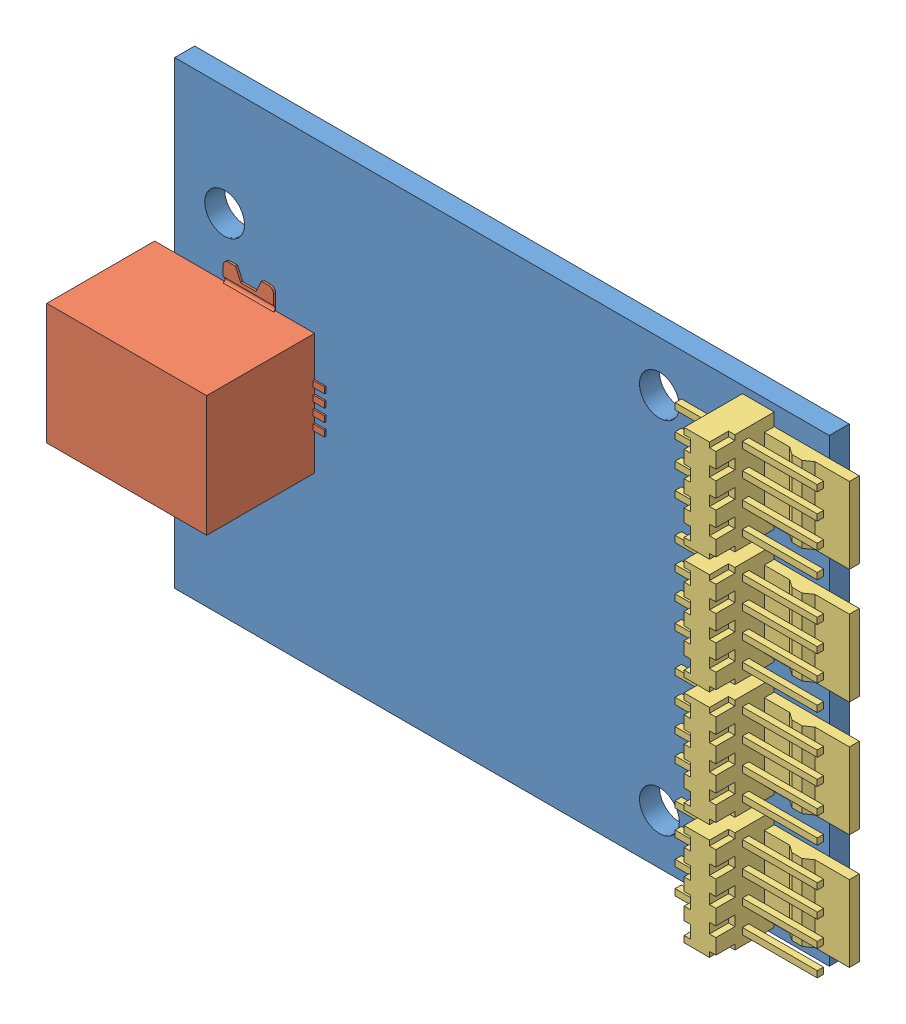
SolidWorks assembly UsbBoard, configuration Défaut. Lengths in mm.
Overall size (70.5 46 14.87).
6 component instances, 3 part files, 5 mates.
Components (placement in the parent):
- UsbBoard-1: UsbBoard [Défaut] at (-58.0315 -11.6271 69) size (65.5 46 2)
- Samtec-USB-B-S-F-B-SM-1: Samtec-USB-B-S-F-B-SM [Default] at (-52.0315 11.4229 76.4) x (0 -1 0) z (-1 0 0) size (16.2 14.87 17.15)
- User Library-molex kk 0_1in latching 4 way vertical header-1: User Library-molex kk 0_1in latching 4 way vertical header [Default] at (0.372 28.5731 73.8702) x (0 -1 0) z (0 0 1) size (10.16 15.24 5.84)
- User Library-molex kk 0_1in latching 4 way vertical header-2: User Library-molex kk 0_1in latching 4 way vertical header [Default] at (0.372 17.0731 73.8702) x (0 -1 0) z (0 0 1) size (10.16 15.24 5.84)
- User Library-molex kk 0_1in latching 4 way vertical header-3: User Library-molex kk 0_1in latching 4 way vertical header [Default] at (0.372 5.5731 73.8702) x (0 -1 0) z (0 0 1) size (10.16 15.24 5.84)
- User Library-molex kk 0_1in latching 4 way vertical header-4: User Library-molex kk 0_1in latching 4 way vertical header [Default] at (0.372 -5.9269 73.8702) x (0 -1 0) z (0 0 1) size (10.16 15.24 5.84)
Mates (geometry in assembly coordinates):
- Coïncidente1: coincident anti-aligned: plane of UsbBoard-1 through (-58.0315 -11.6271 71) normal (0 0 1); plane of Samtec-USB-B-S-F-B-SM-1 through (-60.0315 17.4729 71) normal (0 0 -1)
- Distance2: distance = 2 mm aligned: plane of UsbBoard-1 through (-58.0315 -11.6271 71) normal (-1 0 0); plane of Samtec-USB-B-S-F-B-SM-1 through (-60.0315 17.4729 71) normal (-1 0 0)
- Distance3: distance = 17 mm aligned: plane of Samtec-USB-B-S-F-B-SM-1 through (-60.0315 5.3729 81.8) normal (0 -1 0); plane of UsbBoard-1 through (-58.0315 -11.6271 71) normal (0 -1 0)
- Coïncidente5: coincident anti-aligned: plane of UsbBoard-1 through (-58.0315 -11.6271 71) normal (0 0 1); plane of User Library-molex kk 0_1in latching 4 way vertical header-1 through (-1.4491 33.8563 71) normal (0 0 -1)
- Distance4: distance = 3 mm aligned: plane of User Library-molex kk 0_1in latching 4 way vertical header-1 through (10.4685 32.5355 70.9769) normal (1 0 0); plane of UsbBoard-1 through (7.4685 -11.6271 71) normal (1 0 0)
